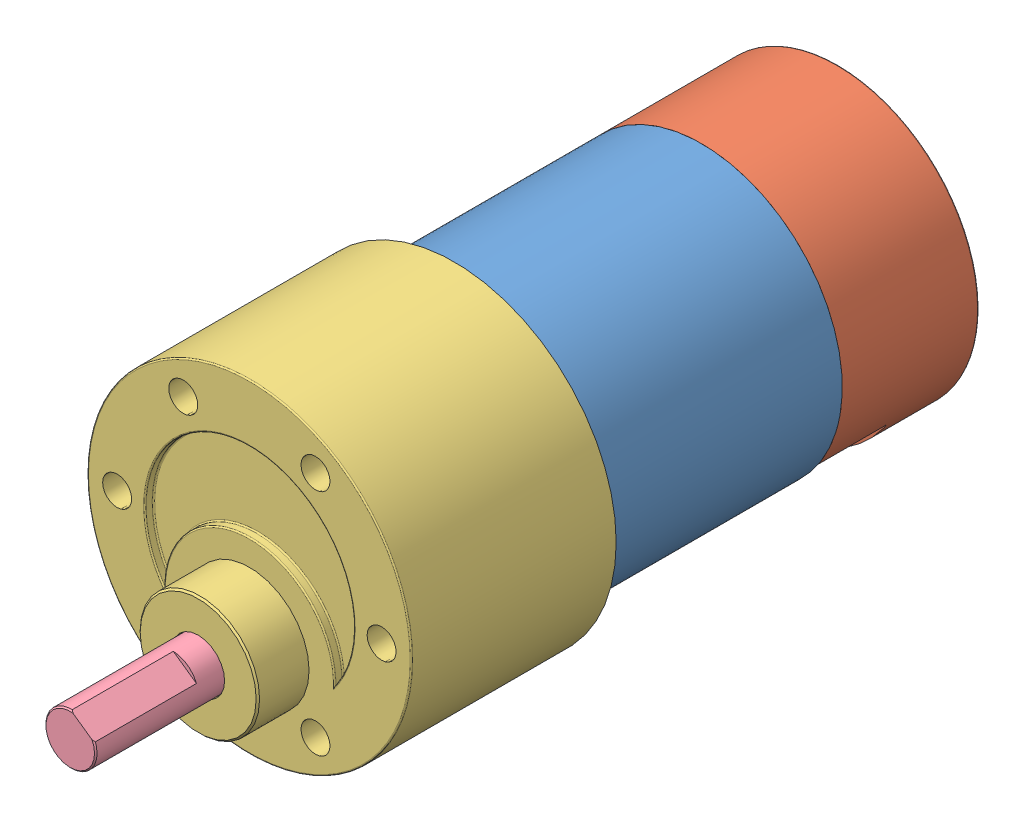
SolidWorks assembly Motor, configuration Default. Lengths in mm.
Overall size (45.64 45.64 90).
4 component instances, 4 part files, 7 mates.
Components (placement in the parent):
- Motor Proper-1: Motor Proper [Default] at (14.2667 22.6871 35.252) x (0.971375 -0.237549 0) z (0 0 1) size (33 33 29)
- Motor Encoder-1: Motor Encoder [Default] at (14.2667 22.6871 20.752) x (0.839139 0.543917 0) z (0 0 1) size (33 33 16)
- Motor Gearbox-1: Motor Gearbox [Default] at (14.2667 22.6871 49.752) size (38 38 30)
- Motor Shaft-1: Motor Shaft [Default] at (14.2667 15.6871 60.752) x (-0.817383 0.576094 0) z (0 0 1) size (6 6 34)
Mates (geometry in assembly coordinates):
- Coincident1: coincident aligned: circle of Motor Gearbox-1; plane of Motor Proper-1 through (14.2667 22.6871 49.752) normal (0 0 1)
- Concentric2: concentric aligned: cylinder of Motor Gearbox-1 through (14.2667 22.6871 73.752) axis (0 0 -1) radius 19; cylinder of Motor Proper-1 through (14.2667 22.6871 49.752) axis (0 0 -1) radius 16.5
- Coincident2: coincident anti-aligned: plane of Motor Encoder-1 through (14.2667 22.6871 20.752) normal (0 0 1); plane of Motor Proper-1 through (14.2667 22.6871 20.752) normal (0 0 -1)
- Concentric5: concentric anti-aligned: cylinder of Motor Proper-1 through (14.2667 22.6871 49.752) axis (0 0 -1) radius 16.5; cylinder of Motor Encoder-1 through (14.2667 22.6871 12.752) axis (0 0 1) radius 16.5
- Parallel1: parallel aligned: plane of Motor Gearbox-1 through (14.2667 22.6871 49.752) normal (0 1 0); plane of assembly through (0 0 0) normal (0 1 0)
- Concentric6: concentric anti-aligned: cylinder of Motor Gearbox-1 through (14.2667 15.6871 59.752) axis (0 0 1) radius 3.1; cylinder of Motor Shaft-1 through (14.2667 15.6871 82.752) axis (0 0 -1) radius 3
- Distance1: distance = 1 mm anti-aligned: plane of Motor Gearbox-1 through (14.2667 15.6871 59.752) normal (0 0 1); plane of Motor Shaft-1 through (14.2667 15.6871 60.752) normal (0 0 -1)
